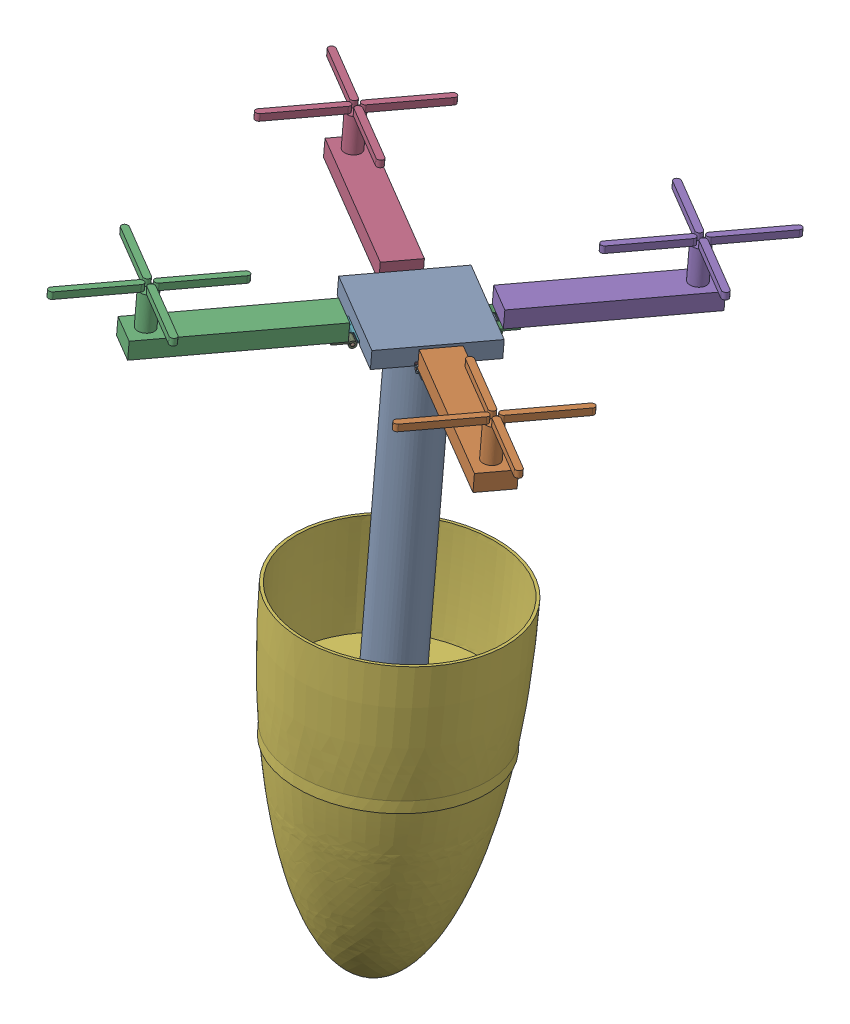
SolidWorks assembly Assem1, configuration Default. Lengths in mm.
Overall size (433.64 496.34 434.65).
10 component instances, 4 part files, 26 mates.
Components (placement in the parent):
- RotorShaft-1: RotorShaft [Default] at (-128.2448 -27.661 255.3781) x (0.857349 0.019329 0.514373) z (-0.514339 0.071398 0.854609) size (76.2 266.7 76.2)
- Rotors-4: Rotors [Default] at (-84.6775 235.3713 259.6236) x (0.514339 -0.071398 -0.854609) z (0.857349 0.019329 0.514373) size (116.84 43.18 172.72)
- Rotors-5: Rotors [Default] at (-145.8825 237.6947 274.805) x (0.857349 0.019329 0.514373) z (-0.514339 0.071398 0.854609) size (116.84 43.18 172.72)
- Rotors-6: Rotors [Default] at (-161.1876 233.6464 213.7208) x (-0.514339 0.071398 0.854609) z (-0.857349 -0.019329 -0.514373) size (116.84 43.18 172.72)
- Rotors-7: Rotors [Default] at (-99.9827 231.323 198.5394) x (-0.857349 -0.019329 -0.514373) z (0.514339 -0.071398 -0.854609) size (116.84 43.18 172.72)
- FS_Elliptical_Nosecone-1: FS_Elliptical_Nosecone [Default] at (-126.6537 50.8633 249.7754) x (-0.951433 -0.002795 -0.307845) z (-0.3072 0.07392 0.94877) size (156.72 254 156.72)
- 1598A12_Mortise-Mount Hinge with Holes-1: 1598A12_Mortise-Mount Hinge with Holes [1598A12] at (-144.6605 229.0122 273.0946) x (-0.514339 0.071398 0.854609) z (0.857349 0.019329 0.514373) size (25.4 4.93 26.67)
- 1598A12_Mortise-Mount Hinge with Holes-2: 1598A12_Mortise-Mount Hinge with Holes [1598A12] at (-87.1731 226.83 258.8353) x (0.857349 0.019329 0.514373) z (0.514339 -0.071398 -0.854609) size (25.4 4.93 26.67)
- 1598A12_Mortise-Mount Hinge with Holes-3: 1598A12_Mortise-Mount Hinge with Holes [1598A12] at (-101.5486 223.0276 201.4612) x (0.514339 -0.071398 -0.854609) z (-0.857349 -0.019329 -0.514373) size (25.4 4.93 26.67)
- 1598A12_Mortise-Mount Hinge with Holes-4: 1598A12_Mortise-Mount Hinge with Holes [1598A12] at (-159.0361 225.2099 215.7205) x (-0.857349 -0.019329 -0.514373) z (-0.514339 0.071398 0.854609) size (25.4 4.93 26.67)
Mates (geometry in assembly coordinates):
- Coincident26: coincident: point of RotorShaft-1; point of 1598A12_Mortise-Mount Hinge with Holes-1
- Coincident36: coincident: point of RotorShaft-1; point of 1598A12_Mortise-Mount Hinge with Holes-2
- Coincident37: coincident: point of RotorShaft-1; point of 1598A12_Mortise-Mount Hinge with Holes-2
- Coincident38: coincident anti-aligned: plane of RotorShaft-1 through (-123.0609 228.1762 237.1241) normal (-0.020207 -0.997261 0.071155); plane of 1598A12_Mortise-Mount Hinge with Holes-2 through (-104.5498 229.6476 263.0024) normal (0.020207 0.997261 -0.071155)
- Coincident42: coincident anti-aligned: plane of Rotors-4 through (17.5453 232.4002 336.2544) normal (-0.020207 -0.997261 0.071155); plane of 1598A12_Mortise-Mount Hinge with Holes-2 through (-82.7732 230.1385 276.0675) normal (0.020207 0.997261 -0.071155)
- Coincident43: coincident: point of RotorShaft-1; point of 1598A12_Mortise-Mount Hinge with Holes-3
- Coincident45: coincident: point of RotorShaft-1; point of 1598A12_Mortise-Mount Hinge with Holes-3
- Coincident46: coincident anti-aligned: plane of RotorShaft-1 through (-123.0609 228.1762 237.1241) normal (-0.020207 -0.997261 0.071155); plane of 1598A12_Mortise-Mount Hinge with Holes-3 through (-97.1487 226.3362 218.6935) normal (0.020207 0.997261 -0.071155)
- Coincident48: coincident anti-aligned: plane of Rotors-7 through (-23.9015 216.1683 96.9884) normal (-0.020207 -0.997261 0.071155); plane of 1598A12_Mortise-Mount Hinge with Holes-3 through (-84.0845 224.5227 196.9864) normal (0.020207 0.997261 -0.071155)
- Coincident49: coincident: point of RotorShaft-1; point of 1598A12_Mortise-Mount Hinge with Holes-4
- Coincident50: coincident: point of RotorShaft-1; point of 1598A12_Mortise-Mount Hinge with Holes-4
- Coincident51: coincident anti-aligned: plane of RotorShaft-1 through (-123.0609 228.1762 237.1241) normal (-0.020207 -0.997261 0.071155); plane of 1598A12_Mortise-Mount Hinge with Holes-4 through (-141.5719 226.7049 211.2457) normal (0.020207 0.997261 -0.071155)
- Coincident54: coincident anti-aligned: plane of Rotors-6 through (-263.6671 223.9523 137.9937) normal (-0.020207 -0.997261 0.071155); plane of 1598A12_Mortise-Mount Hinge with Holes-4 through (-163.3486 226.2139 198.1806) normal (0.020207 0.997261 -0.071155)
- Coincident56: coincident anti-aligned: plane of RotorShaft-1 through (-123.0609 228.1762 237.1241) normal (-0.020207 -0.997261 0.071155); plane of 1598A12_Mortise-Mount Hinge with Holes-1 through (-148.9731 230.0163 255.5547) normal (0.020207 0.997261 -0.071155)
- Coincident57: coincident: point of RotorShaft-1; point of 1598A12_Mortise-Mount Hinge with Holes-1
- Coincident60: coincident anti-aligned: line of Rotors-7 through (-23.9015 216.1683 96.9884) axis (-0.514339 0.071398 0.854609); line of 1598A12_Mortise-Mount Hinge with Holes-3 through (-89.7367 225.3073 206.3778) axis (0.514339 -0.071398 -0.854609)
- Coincident61: coincident aligned: line of Rotors-4 through (-91.3379 229.9454 270.929) axis (0.514339 -0.071398 -0.854609); line of 1598A12_Mortise-Mount Hinge with Holes-2 through (-86.8526 229.3228 263.4763) axis (0.514339 -0.071398 -0.854609)
- Coincident62: coincident aligned: line of Rotors-5 through (-156.8991 231.1166 268.7243) axis (0.857349 0.019329 0.514373); line of 1598A12_Mortise-Mount Hinge with Holes-1 through (-149.4225 231.2851 273.21) axis (0.857349 0.019329 0.514373)
- Coincident63: coincident anti-aligned: plane of Rotors-5 through (-222.2202 240.1842 377.2597) normal (-0.020207 -0.997261 0.071155); plane of 1598A12_Mortise-Mount Hinge with Holes-1 through (-162.0373 231.8298 277.2617) normal (0.020207 0.997261 -0.071155)
- Coincident64: coincident aligned: line of Rotors-7 through (-89.2226 225.2359 205.5238) axis (-0.857349 -0.019329 -0.514373); line of 1598A12_Mortise-Mount Hinge with Holes-3 through (-96.6993 225.0673 201.0381) axis (-0.857349 -0.019329 -0.514373)
- Coincident66: coincident aligned: line of Rotors-6 through (-154.7838 226.407 203.3191) axis (-0.514339 0.071398 0.854609); line of 1598A12_Mortise-Mount Hinge with Holes-4 through (-159.2692 227.0297 210.7719) axis (-0.514339 0.071398 0.854609)
- Coincident67: coincident anti-aligned: line of Rotors-6 through (-263.6671 223.9523 137.9937) axis (0.857349 0.019329 0.514373); line of 1598A12_Mortise-Mount Hinge with Holes-4 through (-153.927 226.4264 203.8331) axis (-0.857349 -0.019329 -0.514373)
- Coincident69: coincident anti-aligned: line of Rotors-5 through (-200.4436 240.6751 390.3248) axis (0.514339 -0.071398 -0.854609); line of 1598A12_Mortise-Mount Hinge with Holes-1 through (-134.6085 231.5362 280.9354) axis (-0.514339 0.071398 0.854609)
- Coincident70: coincident anti-aligned: line of Rotors-4 through (17.5453 232.4002 336.2544) axis (-0.857349 -0.019329 -0.514373); line of 1598A12_Mortise-Mount Hinge with Holes-2 through (-92.1947 229.9261 270.415) axis (0.857349 0.019329 0.514373)
- Coincident71: coincident anti-aligned: line of Rotors-7 through (-23.9015 216.1683 96.9884) axis (-0.514339 0.071398 0.854609); line of 1598A12_Mortise-Mount Hinge with Holes-3 through (-89.7367 225.3073 206.3778) axis (0.514339 -0.071398 -0.854609)
- Coincident77: coincident aligned: circle of RotorShaft-1; circle of FS_Elliptical_Nosecone-1
